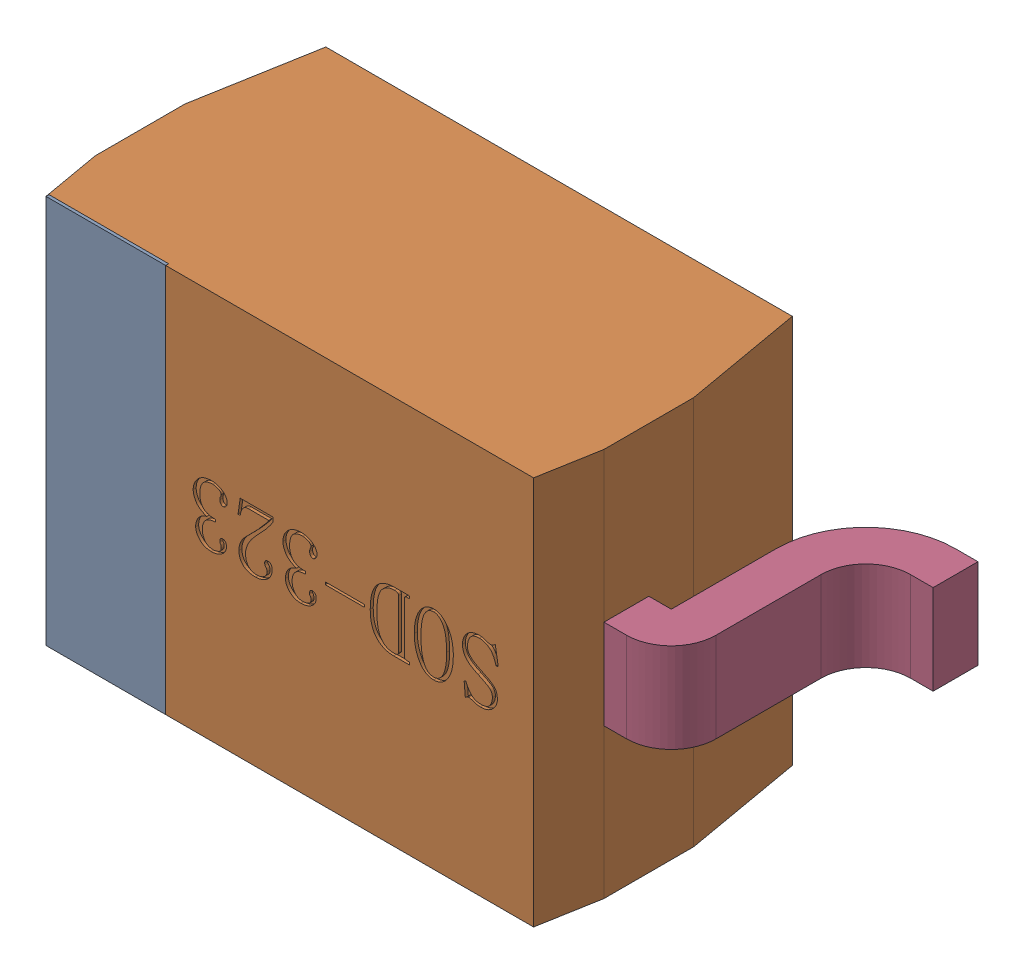
SolidWorks assembly D3, configuration 默认. Lengths in mm.
Overall size (2.6 1.3 1).
5 component instances, 4 part files, 0 mates.
Components (placement in the parent):
- D3-subassembly-1-1: D3-subassembly-1 [默认] at (24.1299 25.7809 0) x (-1 0 0) z (0 0 1) size (2.6 1.3 1)
  - SOD-323-1: SOD-323 [默认] at origin size (0.4 1.3 0.01)
  - SOD-323-1-1: SOD-323-1 [默认] at origin size (1.7 1.3 0.9)
  - SOD-323-2-1: SOD-323-2 [默认] at origin size (0.45 0.3 0.8)
  - SOD-323-3-1: SOD-323-3 [默认] at origin size (0.45 0.3 0.8)
